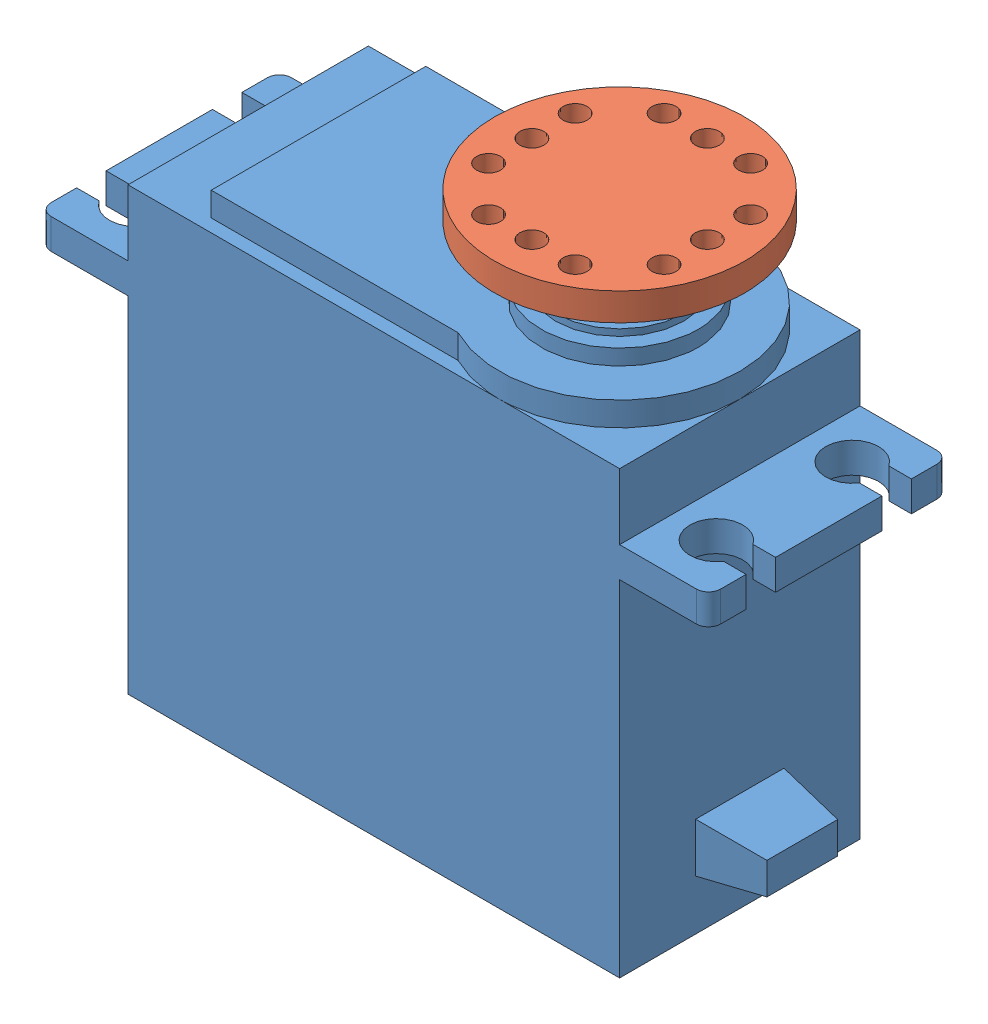
SolidWorks assembly 어셈블리7, configuration 기본. Lengths in mm.
Overall size (55.7 46.85 20.8).
2 component instances, 2 part files, 5 mates.
Components (placement in the parent):
- mg946r-1: mg946r [기본] at (2.0449 0 33.425) x (1 0 0) z (0 1 0) size (55.7 20 44.55)
- HN1_MG946R-1: HN1_MG946R [기본] at (2.0449 44.55 33.425) x (1 0 0) z (0 1 0) size (20.8 20.8 5.3)
Mates (geometry in assembly coordinates):
- 일치1: coincident anti-aligned: plane of mg946r-1 through (2.0449 0 33.425) normal (0 -1 0); plane of assembly through (0 0 0) normal (0 1 0)
- 상대 고정1: in place: plane of mg946r-1 through (12.4949 44.55 33.425) normal (0 1 0); plane of ? through (0 44.55 0) normal (0 1 0); moOrthogonalPlaneRef_w of mg946r-1 through (12.4949 44.55 33.425) normal (0 1 0); plane of ? through (0 44.55 0) normal (0 0 -1); plane of mg946r-1 through (12.4949 44.55 33.425) normal (0 1 0); line of ? through (-55 0 44.55) axis (0 1 0); plane of mg946r-1 through (12.4949 44.55 33.425) normal (0 1 0); unknown of HN1_MG946R-1
- 일치2: coincident aligned: plane of mg946r-1; plane of HN1_MG946R-1
- 일치3: coincident aligned: moOrthogonalPlaneRef_w of mg946r-1 through (2.0449 44.55 33.425) normal (0 0 -1); plane of HN1_MG946R-1 through (2.0449 44.55 33.425) normal (0 0 -1)
- 일치4: coincident anti-aligned: moOrthogonalPlaneRef_w of mg946r-1 through (2.0449 44.55 33.425) normal (-1 0 0); plane of HN1_MG946R-1
